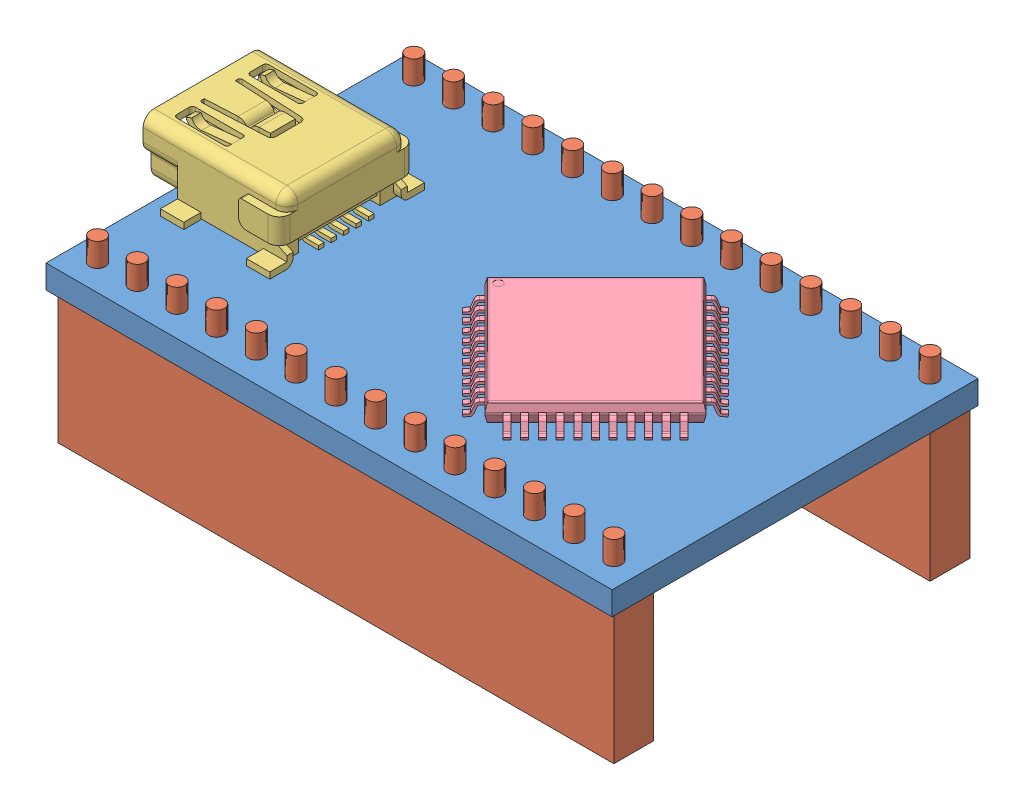
SolidWorks assembly u4_dev, configuration Default. Lengths in mm.
Overall size (37.35 14.14 23.4).
5 component instances, 4 part files, 7 mates.
Components (placement in the parent):
- U4_dev_board-1: U4_dev_board [Default] at (-59.314 11.6418 25.0293) size (36.2 1.5 23.4)
- header_1x14-1: header_1x14 [Default] at (-58.982 11.6418 22.0655) x (1 0 0) z (0 -1 0) size (35.56 2.54 11.5)
- header_1x14-2: header_1x14 [Default] at (-58.9753 11.6418 1.8514) x (1 0 0) z (0 -1 0) size (35.56 2.54 11.5)
- usb_microb-1: usb_microb [Default] at (-60.46 15.1418 13.8229) x (0 0 1) z (-1 0 0) size (9.9 5.09 9.49)
- User Library-IPC QFP-full-1: User Library-IPC QFP-full [QFP80P1200X1200X120-45N MS-026 PGS] at (-36.1746 13.1418 13.03) x (0.707107 0 -0.707107) z (0.707107 0 0.707107) size (12.02 1.35 12.02)
Mates (geometry in assembly coordinates):
- Coincident1: coincident anti-aligned: plane of U4_dev_board-1 through (-59.314 11.6418 25.0293) normal (0 -1 0); plane of header_1x14-1 through (-58.982 11.6418 24.6055) normal (0 1 0)
- Coincident2: coincident anti-aligned: plane of U4_dev_board-1 through (-59.314 11.6418 25.0293) normal (0 -1 0); plane of header_1x14-2 through (-58.9753 11.6418 4.3914) normal (0 1 0)
- Coincident3: coincident anti-aligned: plane of U4_dev_board-1 through (-59.314 13.1418 25.0293) normal (0 1 0); plane of usb_microb-1 through (-56.73 13.1418 8.8509) normal (0 -1 0)
- Parallel1: parallel aligned: plane of U4_dev_board-1 through (-59.314 13.1418 25.0293) normal (-1 0 0); plane of usb_microb-1 through (-60.46 13.1138 9.8189) normal (-1 0 0)
- Coincident5: coincident: plane of U4_dev_board-1 through (-59.314 13.1418 25.0293) normal (0 1 0); line of User Library-IPC QFP-full-1 through (-29.2321 13.1418 14.5728) axis (0.707107 0 -0.707107)
- Coincident6: coincident: plane of U4_dev_board-1 through (-59.314 13.1418 25.0293) normal (0 1 0); line of User Library-IPC QFP-full-1 through (-34.889 13.1418 5.8304) axis (0.707107 0 0.707107)
- Angle1: planar angle = 0.785398 rad aligned: plane of User Library-IPC QFP-full-1 through (-36.1746 14.4918 20.1011) normal (-0.707107 0 0.707107); plane of U4_dev_board-1 through (-59.314 13.1418 25.0293) normal (0 0 1)
